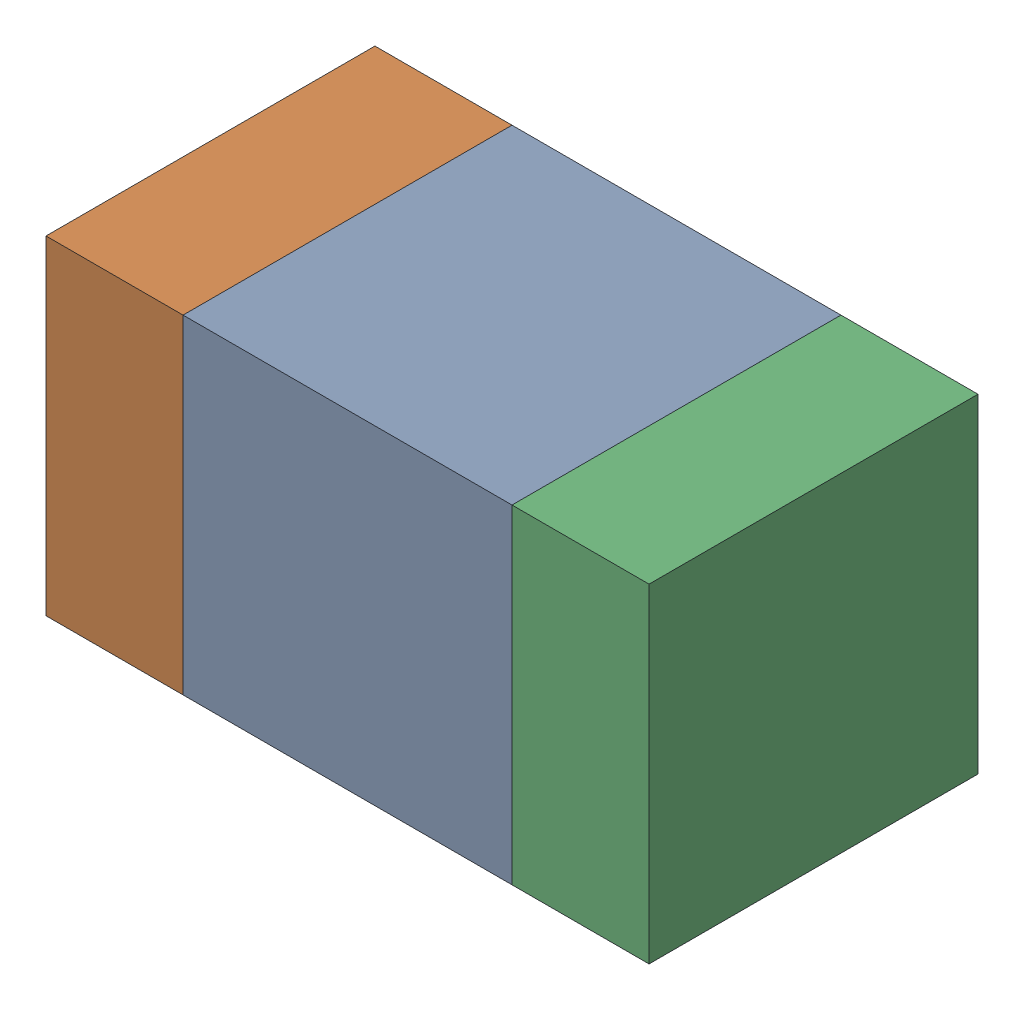
SolidWorks assembly C407PCB, configuration Default. Lengths in mm.
Overall size (1.1 0.6 0.6).
6 component instances, 2 part files, 0 mates.
Components (placement in the parent):
- 761606048-1: 761606048 [Default] at (120.7 102.1 0) size (0.6 0.6 0.6)
  - Extruded_9-1: Extruded_9 [Default] at origin size (0.6 0.6 0.6)
- 854785160-1: 854785160 [Default] at (120.275 102.1 0) size (0.25 0.6 0.6)
  - Extruded_19-1: Extruded_19 [Default] at origin size (0.25 0.6 0.6)
- 854785160-2: 854785160 [Default] at (121.125 102.1 0) size (0.25 0.6 0.6)
  - Extruded_19-1: Extruded_19 [Default] at origin size (0.25 0.6 0.6)
